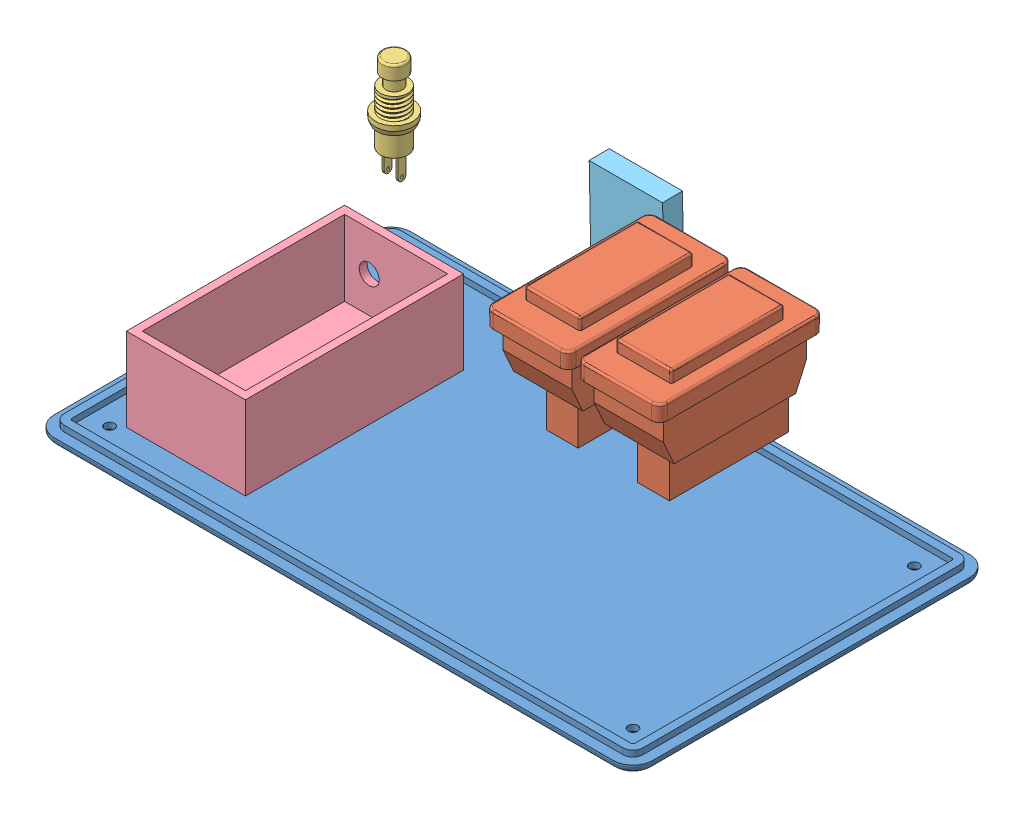
SolidWorks assembly Пульт в сборе, configuration По умолчанию. Lengths in mm.
Overall size (153.02 63.48 92.02).
8 component instances, 6 part files, 15 mates.
Components (placement in the parent):
- Коробка 90х150х53 в сборе-BOT01-1: Коробка 90х150х53 в сборе-BOT01 [По умолчанию] at origin size (153.02 53.98 92.02)
  - Коробка 90х150х53 коробка-BOT01-1: Коробка 90х150х53 коробка-BOT01 [По умолчанию] at origin size (151 53.5 90) (hidden)
  - Коробка 90х150х53 дно-BOT01-1: Коробка 90х150х53 дно-BOT01 [По умолчанию] at (0 2.0374 0) x (1 0 0) z (0 1 0) size (153.02 92.02 4.01)
- Кнопка 3D-001-1: Кнопка 3D-001 [По умолчанию] at (44.0926 53.5 -3.3426) x (0 0 1) z (-1 0 0) size (41.5 28 21)
- Кнопка 3D-001-2: Кнопка 3D-001 [По умолчанию] at (21.0926 53.5 -3.3426) x (0 0 1) z (-1 0 0) size (41.5 28 21)
- Кнопка 2D-001-1: Кнопка 2D-001 [По умолчанию] at (-50.0921 48.5 -20.3767) size (9.5 26.5 9.5)
- Бокс для Крона-1: Бокс для Крона [По умолчанию] at (-33.6192 2.0374 -21.412) x (-1 0 0) z (0 0 -1) size (30 21 55)
- Arduino NANO-1: Arduino NANO [По умолчанию] at (-17.1286 48.5467 -41.5921) x (0 -0.999825 -0.018688) z (-1 0 0) size (42 5 18.5)
Mates (geometry in assembly coordinates):
- Параллельность1: parallel: line of Коробка 90х150х53 в сборе-BOT01-1/Коробка 90х150х53 коробка-BOT01-1 through (69.5926 53.5 39.0926) axis (0 0 -1); line of Кнопка 3D-001-1 through (33.5926 53.5 -22.0926) axis (0 0 1)
- Совпадение2: coincident: plane of Коробка 90х150х53 в сборе-BOT01-1/Коробка 90х150х53 коробка-BOT01-1 through (-74.5 53.5 -205.1975) normal (0 1 0); plane of Кнопка 3D-001-1 through (44.0926 53.5 -3.3426) normal (0 -1 0)
- Расстояние1: distance = 15 mm: line of Кнопка 3D-001-1 through (54.5926 53.5 15.4074) axis (0 0 -1); line of Коробка 90х150х53 в сборе-BOT01-1/Коробка 90х150х53 коробка-BOT01-1 through (69.5926 53.5 39.0926) axis (0 0 -1)
- Расстояние2: distance = 15 mm: line of Коробка 90х150х53 в сборе-BOT01-1/Коробка 90х150х53 коробка-BOT01-1 through (69.5926 53.5 -39.0926) axis (-1 0 0); line of Кнопка 3D-001-1 through (52.5926 53.5 -24.0926) axis (-1 0 0)
- Совпадение5: coincident: plane of Коробка 90х150х53 в сборе-BOT01-1/Коробка 90х150х53 коробка-BOT01-1 through (-74.5 53.5 -205.1975) normal (0 1 0); plane of Кнопка 3D-001-2 through (21.0926 53.5 -3.3426) normal (0 -1 0)
- Совпадение6: coincident: plane of Кнопка 3D-001-1 through (54.5926 57.5 17.4074) normal (0 0 1); plane of Кнопка 3D-001-2 through (31.5926 57.5 17.4074) normal (0 0 1)
- Расстояние3: distance = 2 mm: plane of Кнопка 3D-001-2 through (31.5926 57.5 -24.0926) normal (1 0 0); plane of Кнопка 3D-001-1 through (33.5926 57.5 -24.0926) normal (-1 0 0)
- Совпадение8: coincident: plane of Коробка 90х150х53 в сборе-BOT01-1/Коробка 90х150х53 коробка-BOT01-1 through (-74.5 51 -205.1975) normal (0 -1 0); plane of Кнопка 2D-001-1 through (-46.5921 51 -20.3767) normal (0 1 0)
- Расстояние6: distance = 20 mm: plane of Кнопка 2D-001-1 through (-52.0921 36.5 -18.3767) normal (-1 0 0); line of Коробка 90х150х53 в сборе-BOT01-1/Коробка 90х150х53 коробка-BOT01-1 through (-72.0921 48.5467 39.0926) axis (0 0 -1)
- Расстояние7: distance = 20 mm: line of Кнопка 2D-001-1 through (-52.0921 43 -22.3767) axis (1 0 0); line of Коробка 90х150х53 в сборе-BOT01-1/Коробка 90х150х53 коробка-BOT01-1 through (-69.5926 48.5467 -41.5921) axis (1 0 0)
- Совпадение15: coincident: cylinder of Коробка 90х150х53 в сборе-BOT01-1/Коробка 90х150х53 коробка-BOT01-1 through (-65.9619 59.4853 35.4619) axis (0 -1 0) radius 3; line of Бокс для Крона-1 through (-63.6192 23.0374 33.588) axis (0 -1 0)
- Совпадение16: coincident: plane of Коробка 90х150х53 в сборе-BOT01-1/Коробка 90х150х53 коробка-BOT01-1 through (-180.2008 53.4533 -41.5004) normal (0 -0.018688 0.999825); plane of Arduino NANO-1 through (-17.1286 48.5467 -41.5921) normal (0 0.018688 -0.999825)
- Совпадение17: coincident: line of Коробка 90х150х53 в сборе-BOT01-1/Коробка 90х150х53 коробка-BOT01-1 through (-69.5926 48.5467 -41.5921) axis (1 0 0); line of Arduino NANO-1 through (1.3714 48.5467 -41.5921) axis (-1 0 0)
- Совпадение18: coincident: plane of Коробка 90х150х53 в сборе-BOT01-1/Коробка 90х150х53 дно-BOT01-1 through (-70.4617 2.0374 39.9617) normal (0 1 0); plane of Бокс для Крона-1 through (-93.6192 2.0374 88.588) normal (0 -1 0)
- Параллельность5: parallel: line of Коробка 90х150х53 в сборе-BOT01-1/Коробка 90х150х53 дно-BOT01-1 through (-70.4629 2.0374 40.4624) axis (1 0 0); line of Бокс для Крона-1 through (-63.6192 2.0374 33.588) axis (1 0 0)
